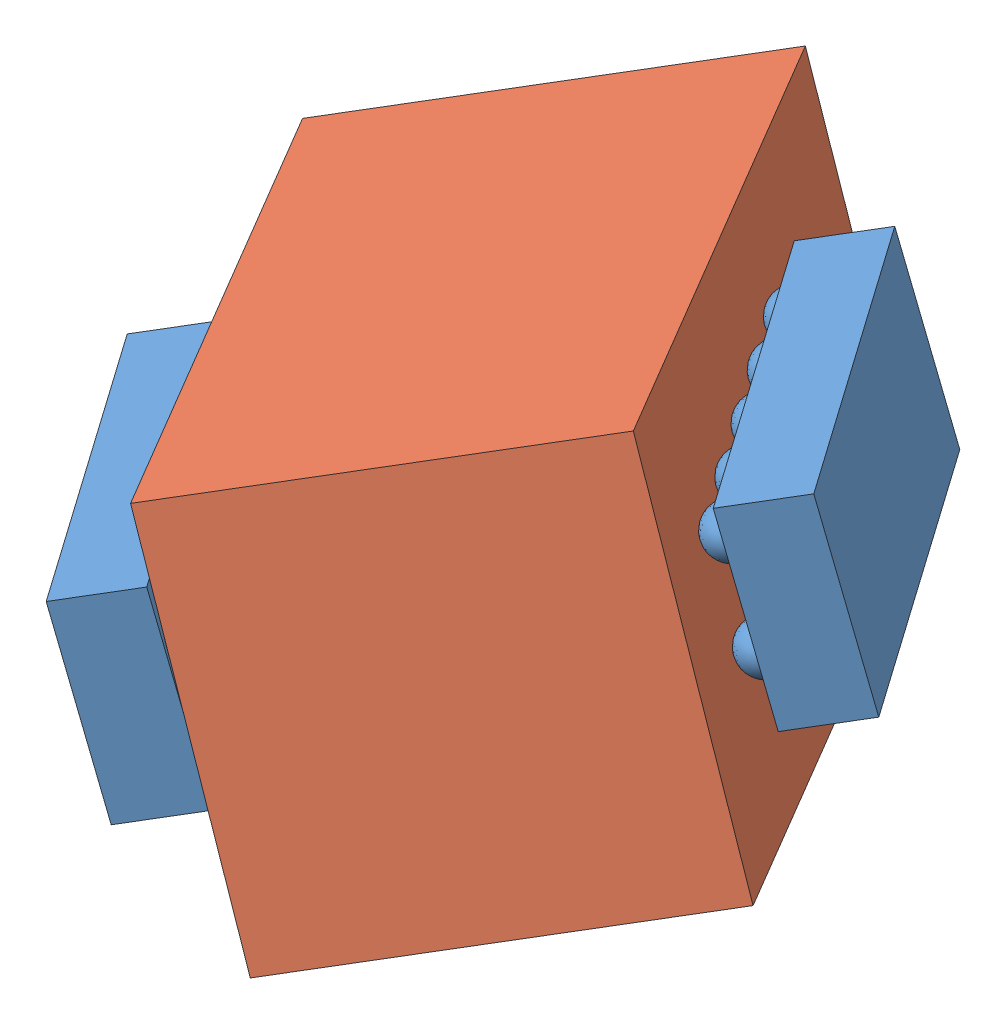
SolidWorks assembly sensorandpeg, configuration Default. Lengths in mm.
Overall size (104.29 77.03 102.39).
3 component instances, 2 part files, 5 mates.
Components (placement in the parent):
- sensor-2: sensor [Default] at (10.9499 24.49 8.6313) x (0.587747 0.073302 0.805717) z (0.768491 0.260763 -0.584315) size (50 25 13.21)
- cube peg-1: cube peg [Default] at (61.6353 44.4906 14.266) x (-0.319459 0.947596 0.002733) z (-0.554407 -0.184565 -0.811522) size (50 50 90)
- sensor-3: sensor [Default] at (69.8229 45.1733 -35.5018) x (0.587747 0.073302 0.805717) z (-0.768491 -0.260763 0.584315) size (50 25 13.21)
Mates (geometry in assembly coordinates):
- 相切2: tangent anti-aligned: sphere of sensor-2; plane of cube peg-1 through (0.1679 -8.0684 -42.6906) normal (-0.768491 -0.260763 0.584315)
- 平行2: parallel aligned: plane of sensor-2 through (18.6348 27.0977 2.7882) normal (0.768491 0.260763 -0.584315); plane of cube peg-1 through (38.5924 4.9697 -71.9063) normal (0.768491 0.260763 -0.584315)
- 相切3: tangent anti-aligned: plane of cube peg-1 through (38.5924 4.9697 -71.9063) normal (0.768491 0.260763 -0.584315); sphere of sensor-3
- 平行3: parallel aligned: plane of cube peg-1 through (38.5924 4.9697 -71.9063) normal (0.768491 0.260763 -0.584315); plane of sensor-3 through (69.8229 45.1733 -35.5018) normal (0.768491 0.260763 -0.584315)
- 重合4: coincident aligned: plane of sensor-2 through (7.2956 13.6249 -18.1377) normal (0.252933 -0.962616 -0.096931); plane of sensor-3 through (50.9862 28.3794 -50.6564) normal (0.252933 -0.962616 -0.096931)
